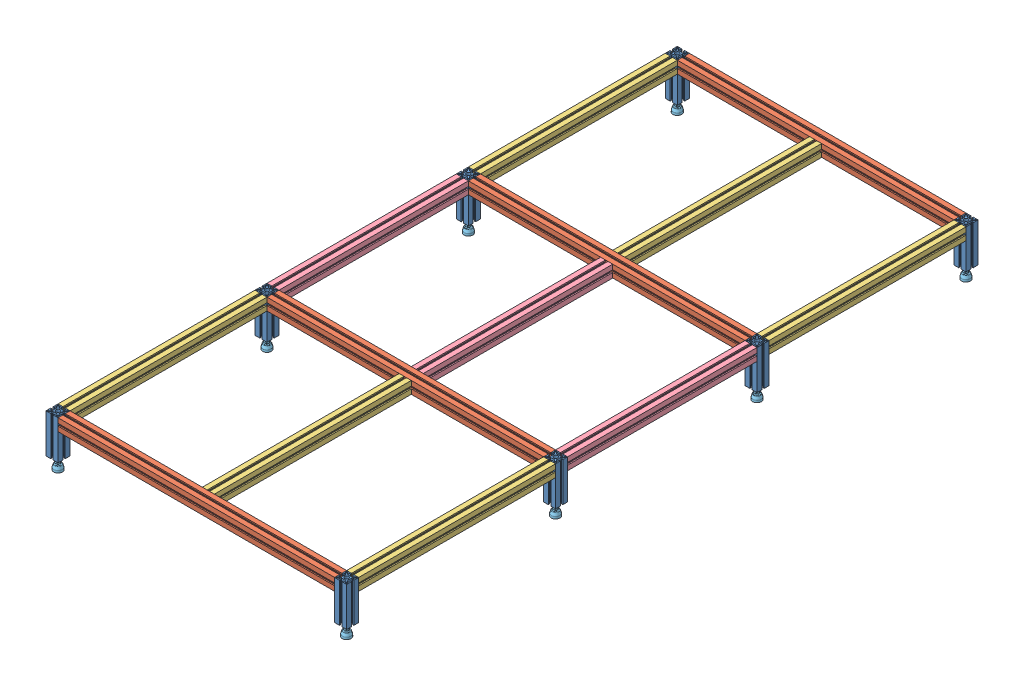
SolidWorks assembly Pd7 00-1-00, configuration Domyślna. Lengths in mm.
Overall size (1000 171 2100).
29 component instances, 5 part files, 0 mates.
Components (placement in the parent):
- Profil 40x40x130-1: Profil 40x40x130 [Default] at (-3435.1327 5278.8484 8183.413) x (-1 0 0) z (0 1 0) size (40 40 130)
- Profil 40x40x130-2: Profil 40x40x130 [Default] at (-4395.1327 5278.8484 8183.413) x (-1 0 0) z (0 1 0) size (40 40 130)
- Profil 40x40x130-3: Profil 40x40x130 [Default] at (-3435.1327 5278.8484 10243.413) x (-1 0 0) z (0 1 0) size (40 40 130)
- Profil 40x40x130-4: Profil 40x40x130 [Default] at (-4395.1327 5278.8484 10243.413) x (-1 0 0) z (0 1 0) size (40 40 130)
- Profil 40x40x130-7: Profil 40x40x130 [Default] at (-3435.1327 5278.8484 9548.413) x (-1 0 0) z (0 1 0) size (40 40 130)
- Profil 40x40x130-8: Profil 40x40x130 [Default] at (-3435.1327 5278.8484 8878.413) x (-1 0 0) z (0 1 0) size (40 40 130)
- Profil 40x40x130-9: Profil 40x40x130 [Default] at (-4395.1327 5278.8484 9548.413) x (-1 0 0) z (0 1 0) size (40 40 130)
- Profil 40x40x130-10: Profil 40x40x130 [Default] at (-4395.1327 5278.8484 8878.413) x (-1 0 0) z (0 1 0) size (40 40 130)
- Profil 40x40x920-1: Profil 40x40x920 [Default] at (-3475.1327 5368.8484 10243.413) x (0 0 1) z (-1 0 0) size (40 40 920)
- Profil 40x40x920-2: Profil 40x40x920 [Default] at (-3475.1327 5368.8484 9548.413) x (0 0 1) z (-1 0 0) size (40 40 920)
- Profil 40x40x920-3: Profil 40x40x920 [Default] at (-3475.1327 5368.8484 8878.413) x (0 0 1) z (-1 0 0) size (40 40 920)
- Profil 40x40x920-4: Profil 40x40x920 [Default] at (-3475.1327 5368.8484 8183.413) x (0 0 1) z (-1 0 0) size (40 40 920)
- Profil 40x40x655-1: Profil 40x40x655 [Default] at (-4435.1327 5368.8484 9588.413) size (40 40 655)
- Profil 40x40x655-2: Profil 40x40x655 [Default] at (-3475.1327 5368.8484 9588.413) size (40 40 655)
- Profil 40x40x655-3: Profil 40x40x655 [Default] at (-4435.1327 5368.8484 8223.413) size (40 40 655)
- Profil 40x40x655-4: Profil 40x40x655 [Default] at (-3475.1327 5368.8484 8223.413) size (40 40 655)
- Profil 40x40x655-5: Profil 40x40x655 [Default] at (-3955.1327 5368.8484 9588.413) size (40 40 655)
- Profil 40x40x655-6: Profil 40x40x655 [Default] at (-3955.1327 5368.8484 8223.413) size (40 40 655)
- Profil 40x40x630-1: Profil 40x40x630 [Default] at (-3955.1327 5368.8484 8918.413) size (40 40 630)
- Profil 40x40x630-2: Profil 40x40x630 [Default] at (-3475.1327 5368.8484 8918.413) size (40 40 630)
- Profil 40x40x630-3: Profil 40x40x630 [Default] at (-4435.1327 5368.8484 8918.413) size (40 40 630)
- b43-10-1: b43-10 [Domyślna] at (-3455.1327 5239.8484 8203.413) x (-0.521027 0 -0.85354) z (0.85354 0 -0.521027) size (29 77 29)
- b43-10-2: b43-10 [Domyślna] at (-3455.1327 5239.8484 8898.413) x (-0.521027 0 -0.85354) z (0.85354 0 -0.521027) size (29 77 29)
- b43-10-3: b43-10 [Domyślna] at (-4415.1327 5239.8484 8203.413) x (-0.521027 0 -0.85354) z (0.85354 0 -0.521027) size (29 77 29)
- b43-10-4: b43-10 [Domyślna] at (-4415.1327 5239.8484 8898.413) x (-0.521027 0 -0.85354) z (0.85354 0 -0.521027) size (29 77 29)
- b43-10-5: b43-10 [Domyślna] at (-4415.1327 5239.8484 9568.413) x (-0.521027 0 -0.85354) z (0.85354 0 -0.521027) size (29 77 29)
- b43-10-6: b43-10 [Domyślna] at (-4415.1327 5239.8484 10263.413) x (-0.521027 0 -0.85354) z (0.85354 0 -0.521027) size (29 77 29)
- b43-10-7: b43-10 [Domyślna] at (-3455.1327 5239.8484 9568.413) x (-0.521027 0 -0.85354) z (0.85354 0 -0.521027) size (29 77 29)
- b43-10-8: b43-10 [Domyślna] at (-3455.1327 5239.8484 10263.413) x (-0.521027 0 -0.85354) z (0.85354 0 -0.521027) size (29 77 29)
